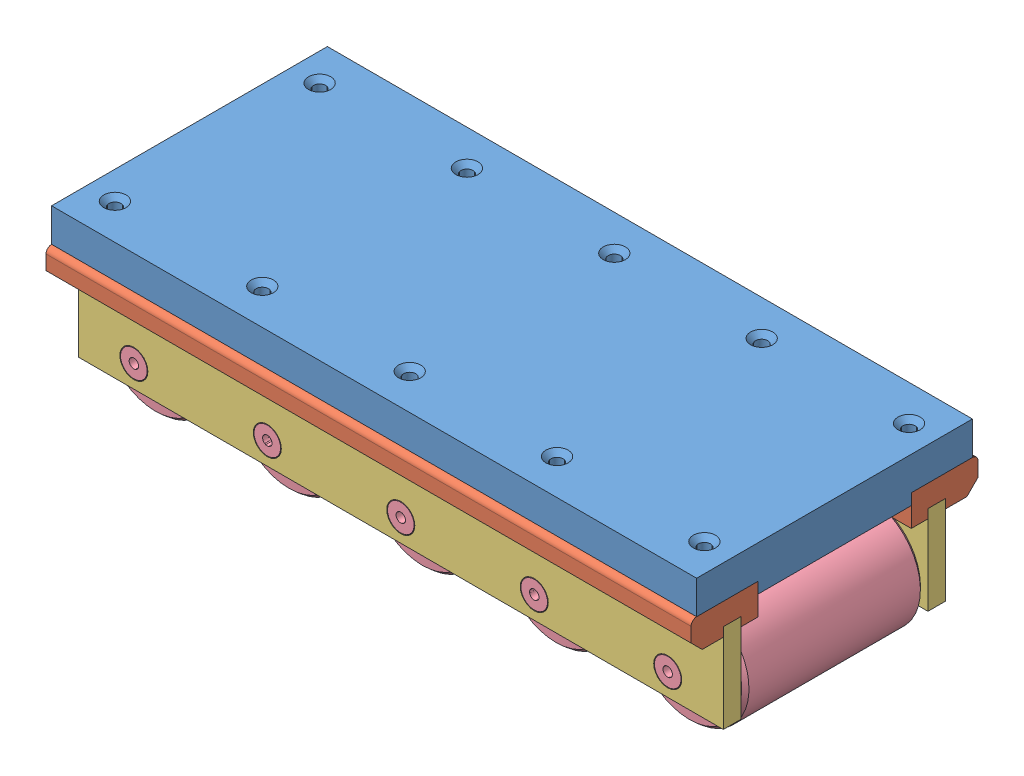
SolidWorks assembly Assem7, configuration Default. Lengths in mm.
Overall size (596.63 168.11 258).
10 component instances, 4 part files, 8 mates.
Components (placement in the parent):
- Part6-1: Part6 [Default] at origin size (580 40 248)
- Part4-1: Part4 [Default] at (-580 10 69) x (0 0 1) z (-1 0 0) size (60 28 580)
- Part4-2: Part4 [Default] at (0 10 -69) x (0 0 -1) z (1 0 0) size (60 28 580)
- Part3-1: Part3 [Default] at (-290 -49.7941 92) size (580 80 16)
- Part3-2: Part3 [Default] at (-290 -49.7941 -92) size (580 80 16)
- Part2-1: Part2 [Default] at (-50 -69.7941 -100) x (0 0 1) z (-0.983063 -0.183268 0) size (200 100 100)
- Part2-2: Part2 [Default] at (-170 -69.7941 -100) x (0 0 1) z (-0.983063 -0.183268 0) size (200 100 100)
- Part2-3: Part2 [Default] at (-290 -69.7941 -100) x (0 0 1) z (-0.983063 -0.183268 0) size (200 100 100)
- Part2-4: Part2 [Default] at (-410 -69.7941 -100) x (0 0 1) z (-0.983063 -0.183268 0) size (200 100 100)
- Part2-5: Part2 [Default] at (-530 -69.7941 -100) x (0 0 1) z (-0.983063 -0.183268 0) size (200 100 100)
Mates (geometry in assembly coordinates):
- Coincident1: coincident anti-aligned: plane of Part6-1 through (-580 10 124) normal (0 -1 0); plane of Part4-1 through (0 10 69) normal (0 1 0)
- Coincident2: coincident anti-aligned: plane of Part6-1 through (-580 10 69) normal (0 0 1); plane of Part4-1 through (0 -17.7941 69) normal (0 0 -1)
- Coincident4: coincident aligned: plane of Part6-1 through (0 0 0) normal (1 0 0); plane of Part4-1 through (0 10 69) normal (1 0 0)
- Coincident5: coincident anti-aligned: plane of Part4-1 through (0 -9.7941 84) normal (0 0 1); plane of Part3-1 through (-290 -49.7941 84) normal (0 0 -1)
- Coincident6: coincident anti-aligned: plane of Part4-1 through (0 -9.7941 100) normal (0 -1 0); plane of Part3-1 through (-580 -9.7941 100) normal (0 1 0)
- Coincident7: coincident aligned: plane of Part4-1 through (0 10 69) normal (1 0 0); plane of Part3-1 through (0 -9.7941 100) normal (1 0 0)
- Concentric1: concentric anti-aligned: circle of Part3-1; cylinder of Part2-1 through (-50 -69.7941 -100) axis (0 0 -1) radius 12.5
- Distance2: distance = 0 mm aligned: plane of Part2-1 through (-50 -69.7941 100) normal (0 0 1); plane of Part3-1 through (-290 -49.7941 100) normal (0 0 1)
